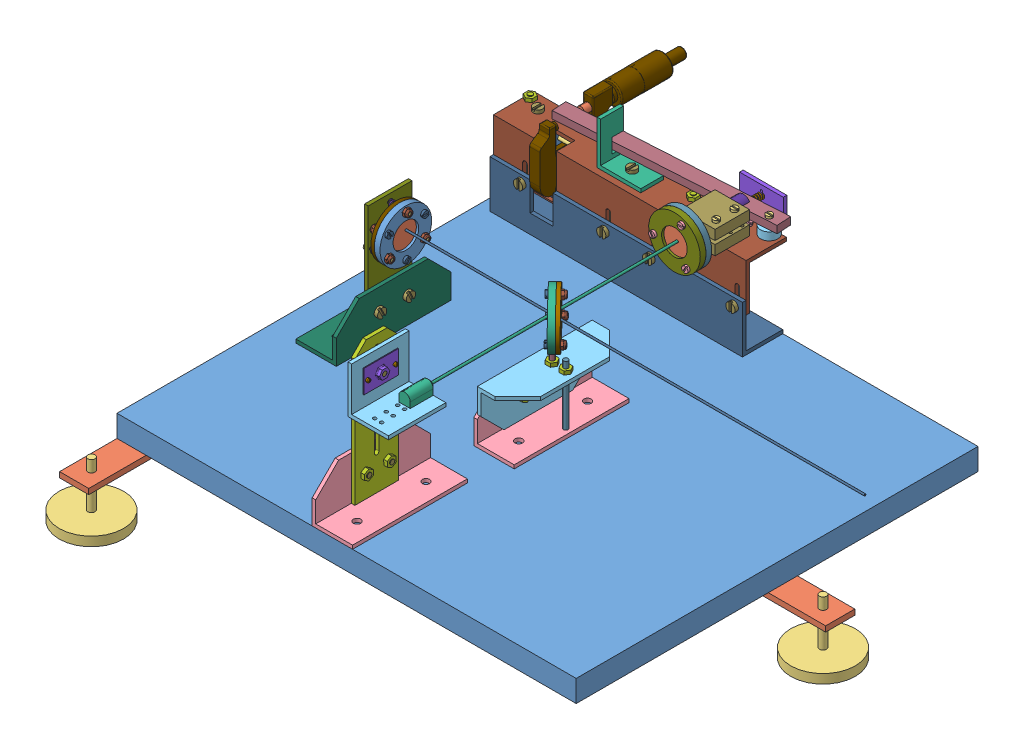
SolidWorks assembly Interferometro, configuration Default. Lengths in mm.
Overall size (495.22 180.12 500.25).
123 component instances, 46 part files, 21 mates.
Components (placement in the parent):
- Baser de Granito-1: Baser de Granito [Default] at (88.5564 -119.9075 34.7333) size (400 19 350)
- Pé de 3 pontos-2: Pé de 3 pontos [Default] at (-311.4436 -124.67 -145.2667) x (0 0 1) z (0 1 0) size (460 450 4.76)
- Pe_manipulo-1: Pe_manipulo [Default] at (-298.7436 -131.4123 69.7333) size (56.25 48 56.25)
- Pe_manipulo-2: Pe_manipulo [Default] at (123.5564 -131.4123 -145.2667) size (56.25 48 56.25)
- Pe_manipulo-3: Pe_manipulo [Default] at (-298.7436 -131.4123 -360.2667) x (0.821021 0 -0.570898) z (0.570898 0 0.821021) size (56.25 48 56.25)
- Suporte do divisor de feixe-1: Suporte do divisor de feixe [Default] at (-129.8734 -86.0499 -144.513) x (0 0 -1) z (1 0 0) size (100 102.86 41.95)
  - Base do divisor-1: Base do divisor [Default] at (-48.2463 -11.7326 33.4299) size (100 41.23 35.2)
  - Base do divisor B-1: Base do divisor B [Default] at (51.7537 28.2674 36.5549) x (-1 0 0) z (0 0 1) size (100 41.23 35.2)
  - Fixador dodivisor de feixe_frontal-1: Fixador dodivisor de feixe_frontal [Default] at (0.0337 65.5054 14.7406) x (0.688011 0 0.7257) z (-0.7257 0 0.688011) size (5 42.5 45)
  - Porca M4-1: Porca M4 [Default] at (1.7537 31.3924 16.5549) size (7.78 3.12 8.95)
  - Porca M4-2: Porca M4 [Default] at (1.7537 25.1424 16.5549) size (7.78 3.12 8.95)
  - Divisor de feixe-1: Divisor de feixe [Default] at (1.4097 65.5054 16.192) x (0.7257 0 -0.688011) z (0.688011 0 0.7257) size (25.4 25.4 3)
  - Arruela do Fixador do divisor de feixe-1: Arruela do Fixador do divisor de feixe [Default] at (3.4737 65.5054 18.3691) x (0.688011 0 0.7257) z (-0.7257 0 0.688011) size (3 42.5 45)
  - Parafuso Padrao M3 10-1: Parafuso Padrao M3 10 [Default] at (-1.3424 83.5054 13.2892) x (0.7257 0 -0.688011) z (0.688011 0 0.7257) size (5.45 5.45 14)
  - Porca M3-1: Porca M3 [Default] at (5.5378 83.5054 20.5462) x (0.725692 0.004853 -0.688003) z (0.003522 -0.999988 -0.003339) size (6.52 3.8 6.82)
  - Parafuso Padrao M3 10-2: Parafuso Padrao M3 10 [Default] at (9.9702 56.5054 2.5642) x (-0.36285 -0.866025 0.344005) z (0.688011 0 0.7257) size (5.45 5.45 14)
  - Parafuso Padrao M3 10-3: Parafuso Padrao M3 10 [Default] at (-12.6549 56.5054 24.0142) x (-0.36285 0.866025 0.344005) z (0.688011 0 0.7257) size (5.45 5.45 14)
  - Porca M3-2: Porca M3 [Default] at (16.8503 56.5054 9.8212) x (-0.359796 -0.868442 0.34111) z (-0.630228 0.495791 0.597497) size (6.52 3.8 6.82)
  - Porca M3-3: Porca M3 [Default] at (-5.7748 56.5054 31.2712) x (-0.365896 0.863589 0.346893) z (0.626707 0.504197 -0.594158) size (6.52 3.8 6.82)
  - Parafuso Padrao M4 16-1: Parafuso Padrao M4 16 [Default] at (14.8037 8.2674 -1.7681) x (1 0 0) z (0 1 0) size (8 13 8)
  - Porca M4-3: Porca M4 [Default] at (14.8037 8.2674 7.6069) x (1 0 0) z (0 1 0) size (7.78 3.12 8.95)
  - Porca M4-5: Porca M4 [Default] at (-11.2963 8.2674 7.6069) x (-0.995163 -0.09824 0) z (0.09824 -0.995163 0) size (7.78 3.12 8.95)
  - Parafuso Padrao M4 16-3: Parafuso Padrao M4 16 [Default] at (-11.2963 8.2674 -1.7681) x (1 0 0) z (0 1 0) size (8 13 8)
  - Haste M4-2: Haste M4 [Default] at (1.7537 20.5054 16.5549) x (0.189668 0 -0.981848) z (0.981848 0 0.189668) size (4 30 4)
  - Haste M4 Longa-2: Haste M4 Longa [Default] at (1.7537 -14.8576 28.4299) size (4 55 4)
  - Porca M4-7: Porca M4 [Default] at (1.7537 25.1424 28.4299) size (7.78 3.12 8.95)
  - Porca M4-8: Porca M4 [Default] at (1.7537 31.3924 28.4299) size (7.78 3.12 8.95)
- Espelho fixo-1: Espelho fixo [Default] at (-245.7834 -84.2987 -136.4219) x (0 0 1) z (-1 0 0) size (100 109.78 49.57)
  - Base do esplho fixo-1: Base do esplho fixo [Default] at (-59.6936 -13.4838 40.6602) size (100 41.23 35.2)
  - Coluna-1: Coluna [Default] at (9.3564 27.4324 8.5872) size (38.1 85 3.12)
  - Mola-1: Mola [Default] at (-9.6747 80.4368 2.5872) size (6.35 5.63 7.54)
  - Mola-2: Mola [Default] at (5.9282 53.474 2.5872) size (6.35 5.63 7.54)
  - Mola-3: Mola [Default] at (-25.1875 53.4779 2.5872) size (6.35 5.63 7.54)
  - Arruela do Fixador-1: Arruela do Fixador [Default] at (-9.6936 62.4324 -0.1128) x (0 0 1) z (-0.5 -0.866025 0) size (3 45 45)
  - Fixador do espelho_frontal-1: Fixador do espelho_frontal [Default] at (-9.6936 62.4324 -5.1128) x (0 0 1) z (-1 0 0) size (5 45 45)
  - Espelho-1: Espelho [Default] at (-9.6936 62.4324 -3.1128) size (25.4 25.4 3)
  - Parafuso Padrao M4 16-1: Parafuso Padrao M4 16 [Default] at (3.3564 6.5162 5.4622) x (0.907366 -0.420341 0) z (0.420341 0.907366 0) size (8 13 8)
  - Porca M4-1: Porca M4 [Default] at (3.3564 6.5162 14.8372) x (1 0 0) z (0 1 0) size (7.78 3.12 8.95)
  - Parafuso Padrao M4 16-2: Parafuso Padrao M4 16 [Default] at (-21.7436 6.5162 5.4622) x (0.907366 -0.420341 0) z (0.420341 0.907366 0) size (8 13 8)
  - Porca M4-2: Porca M4 [Default] at (-21.7436 6.5162 14.8372) x (1 0 0) z (0 1 0) size (7.78 3.12 8.95)
  - Parafuso Padrao M3 20-1: Parafuso Padrao M3 20 [Default] at (-9.6936 80.4324 13.7122) x (-0.923728 -0.383049 0) z (0 0 -1) size (5.45 5.45 22)
  - Porca M3-1: Porca M3 [Default] at (-9.6936 80.4324 -5.1128) x (1 0 0) z (0 1 0) size (6.52 3.8 6.82)
  - Parafuso Padrao M3 20-2: Parafuso Padrao M3 20 [Default] at (-25.282 53.4324 13.7122) x (0.793594 -0.608447 0) z (0 0 -1) size (5.45 5.45 22)
  - Parafuso Padrao M3 20-3: Parafuso Padrao M3 20 [Default] at (5.8949 53.4324 13.7122) x (0.130134 0.991496 0) z (0 0 -1) size (5.45 5.45 22)
  - Porca M3-2: Porca M3 [Default] at (-25.282 53.4324 -5.1128) x (-0.5 0.866025 0) z (-0.866025 -0.5 0) size (6.52 3.8 6.82)
  - Porca M3-3: Porca M3 [Default] at (5.8949 53.4324 -5.1128) x (-0.5 -0.866025 0) z (0.866025 -0.5 0) size (6.52 3.8 6.82)
  - Parafuso Padrao M3 10-1: Parafuso Padrao M3 10 [Default] at (-25.282 71.4324 -7.1128) size (5.45 5.45 14)
  - Porca M3-4: Porca M3 [Default] at (-25.3144 72.932 2.8872) x (1 0 0) z (0 -1 0) size (6.52 3.8 6.82)
  - Porca M3-5: Porca M3 [Default] at (-10.9761 43.6545 2.8872) x (-0.5 0.866025 0) z (0.866025 0.5 0) size (6.52 3.8 6.82)
  - Porca M3-6: Porca M3 [Default] at (7.2099 70.7106 2.8872) x (-0.5 -0.866025 0) z (-0.866025 0.5 0) size (6.52 3.8 6.82)
  - Parafuso Padrao M3 10-2: Parafuso Padrao M3 10 [Default] at (-9.6936 44.4324 -7.1128) x (-0.5 0.866025 0) z (0 0 1) size (5.45 5.45 14)
  - Parafuso Padrao M3 10-3: Parafuso Padrao M3 10 [Default] at (5.8949 71.4324 -7.1128) x (-0.5 -0.866025 0) z (0 0 1) size (5.45 5.45 14)
- Suporte do LASER-1: Suporte do LASER [Default] at (-143.3517 -88.5516 -23.7006) x (0 0 -1) z (1 0 0) size (299 123.12 44.45)
  - Base do LASER-1: Base do LASER [Default] at (-58.434 -9.2309 37.1061) size (100 41.23 35.2)
  - Base do LASER 2-1: Base do LASER 2 [Default] at (-33.434 63.8941 43.3561) size (50 41.23 35.2)
  - Parafuso Padrao M4 16-1: Parafuso Padrao M4 16 [Default] at (1.566 10.7691 1.9081) x (-0.976419 -0.215883 0) z (0.215883 -0.976419 0) size (8 13 8)
  - Porca M4-1: Porca M4 [Default] at (1.566 10.7691 8.1581) x (1 0 0) z (0 -1 0) size (7.78 3.12 8.95)
  - Parafuso Padrao M4 16-2: Parafuso Padrao M4 16 [Default] at (-8.434 84.0234 5.0331) x (1 0 0) z (0 1 0) size (8 13 8)
  - LASER-1: LASER [Default] at (16.566 68.8941 27.3561) x (0 0 1) z (-1 0 0) size (10 10 244)
  - Coluna do LASER-2: Coluna do LASER [Default] at (10.616 -9.2309 5.0331) size (38.1 120 3.12)
  - Porca M4-3: Porca M4 [Default] at (-18.434 10.7691 8.1581) x (1 0 0) z (0 -1 0) size (7.78 3.12 8.95)
  - Parafuso Padrao M4 16-3: Parafuso Padrao M4 16 [Default] at (-18.434 10.7691 1.9081) x (-0.976419 -0.215883 0) z (0.215883 -0.976419 0) size (8 13 8)
  - Porca M4 com grampo-1: Porca M4 com grampo [Default] at (-8.434 84.0234 12.0331) x (0 -1 0) z (-1 0 0) size (20 3.88 30)
  - Parafuso 22-1: Parafuso 22 [Default] at (-20.434 84.0234 12.0331) x (1 0 0) z (0 -1 0) size (3.2 5.55 3.24)
  - Parafuso 22-2: Parafuso 22 [Default] at (3.566 84.0234 12.0331) x (1 0 0) z (0 -1 0) size (3.2 5.55 3.24)
- Espelho regulavel-1: Espelho regulavel [Default] at (-164.1321 -91.633 -267.4552) x (-1 0 0) z (0 0 -1) size (220.22 110.65 148.54)
  - Base fixa do espelho Regulavel-1: Base fixa do espelho Regulavel [Default] at (-82.6886 -6.1494 47.8115) size (220 41.23 35.2)
  - Base do espelho Regulavel-1: Base do espelho Regulavel [Default] at (117.3114 58.8506 50.9365) x (-1 0 0) z (0 0 1) size (220 41.23 35.2)
  - Trilo de Nylon-1: Trilo de Nylon [Default] at (-65.6886 61.9756 35.7385) x (-1 0 0) z (0 0 -1) size (30 20 30)
  - Alvanca de reducao-1: Alvanca de reducao [Default] at (102.5165 75.1506 43.9693) x (0.998146 0 -0.060863) z (-0.060863 0 -0.998146) size (185 6.35 14.7)
  - Arruela do Fixador fechada-1: Arruela do Fixador fechada [Default] at (-47.6886 71.9756 -1.5991) x (0 0 -1) z (0.923728 0.383049 0) size (5 45 45)
  - Parafuso Padrao M5-1: Parafuso Padrao M5 [Default] at (-47.6886 71.9756 -6.5991) x (0.994046 0.108962 0) z (0.108962 -0.994046 0) size (10 12 9.8)
  - Espelho-1: Espelho [Default] at (-47.6886 71.9756 -9.5991) size (25.4 25.4 3)
  - Fixador do espelho_frontal_movel-1: Fixador do espelho_frontal_movel [Default] at (-47.6886 71.9756 -11.5991) x (0 0 1) z (-0.923728 -0.383049 0) size (5 45 45)
  - Guia linear-3: Guia linear [Default] at (-47.6886 71.9756 48.4009) x (-1 0 0) z (0 0 -1) size (12.7 12.7 60)
  - Micrometro-1: Micrometro [Default] at (96.6114 48.8506 52.9365) x (0 0 1) z (-1 0 0) size (128.44 56.67 19.2)
  - Base do micrometro A-1: Base do micrometro A [Default] at (47.1134 55.7256 50.9365) x (0 0 -1) z (-1 0 0) size (25 41.23 35.2)
  - Base do micrometro A-2: Base do micrometro A [Default] at (137.3114 55.7256 25.9365) x (0 0 1) z (1 0 0) size (25 41.23 35.2)
  - Eixo do micrometro-1: Eixo do micrometro [Default] at (92.1114 71.9235 96.5779) x (0.963366 0.268189 0) z (-0.268189 0.963366 0) size (7 50 7)
  - Parafuso Padrao M4-1: Parafuso Padrao M4 [Default] at (79.1864 22.6256 38.4365) x (0 1 0) z (0 0 1) size (8 33 8)
  - Porca M4-1: Porca M4 [Default] at (108.3634 22.6256 38.4365) x (0 1 0) z (0 0 1) size (7.78 3.12 8.95)
  - Parafuso Padrao M4-2: Parafuso Padrao M4 [Default] at (79.1864 51.1928 38.4365) x (0 1 0) z (0 0 1) size (8 33 8)
  - Porca M4-2: Porca M4 [Default] at (108.3634 51.1928 38.4365) x (0 1 0) z (0 0 1) size (7.78 3.12 8.95)
  - Parafuso Padrao M4 16-1: Parafuso Padrao M4 16 [Default] at (121.2749 61.9756 38.4365) size (8 13 8)
  - Parafuso Padrao M4 16-2: Parafuso Padrao M4 16 [Default] at (63.1499 61.9756 38.4365) size (8 13 8)
  - Porca M4-3: Porca M4 [Default] at (121.2749 52.6006 38.4365) size (7.78 3.12 8.95)
  - Porca M4-4: Porca M4 [Default] at (63.1499 52.6006 38.4365) size (7.78 3.12 8.95)
  - Parafuso Padrao M3-1: Parafuso Padrao M3 [Default] at (-63.1886 56.8506 21.7385) x (-0.377487 0 -0.926015) z (0 1 0) size (5.45 5.45 12)
  - Parafuso Padrao M3-2: Parafuso Padrao M3 [Default] at (-63.1886 56.8506 31.7385) x (-0.377487 0 -0.926015) z (0 1 0) size (5.45 5.45 12)
  - Parafuso Padrao M3-3: Parafuso Padrao M3 [Default] at (-38.1886 56.8506 21.7385) x (-0.377487 0 -0.926015) z (0 1 0) size (5.45 5.45 12)
  - Parafuso Padrao M3-4: Parafuso Padrao M3 [Default] at (-38.1886 56.8506 31.7385) x (-0.377487 0 -0.926015) z (0 1 0) size (5.45 5.45 12)
  - Parafuso Padrao M3 20-1: Parafuso Padrao M3 20 [Default] at (-59.6886 83.9756 12.7385) x (1 0 0) z (0 -1 0) size (5.45 5.45 22)
  - Parafuso Padrao M3 20-2: Parafuso Padrao M3 20 [Default] at (-59.6886 83.9756 28.7385) x (1 0 0) z (0 -1 0) size (5.45 5.45 22)
  - Parafuso Padrao M4 16-3: Parafuso Padrao M4 16 [Default] at (-75.1886 25.7256 12.6135) x (1 0 0) z (0 1 0) size (8 13 8)
  - Parafuso Padrao M4 16-4: Parafuso Padrao M4 16 [Default] at (-2.6886 25.7256 12.6135) x (1 0 0) z (0 1 0) size (8 13 8)
  - Parafuso Padrao M4 16-5: Parafuso Padrao M4 16 [Default] at (37.3114 25.7256 12.6135) x (1 0 0) z (0 1 0) size (8 13 8)
  - Parafuso Padrao M4 16-6: Parafuso Padrao M4 16 [Default] at (109.8114 25.7256 12.6135) x (1 0 0) z (0 1 0) size (8 13 8)
  - Porca M4-5: Porca M4 [Default] at (37.3114 25.7256 21.9885) x (1 0 0) z (0 1 0) size (7.78 3.12 8.95)
  - Porca M4-6: Porca M4 [Default] at (109.8114 25.7256 21.9885) x (1 0 0) z (0 1 0) size (7.78 3.12 8.95)
  - Porca M4-7: Porca M4 [Default] at (-75.1886 25.7256 21.9885) x (1 0 0) z (0 1 0) size (7.78 3.12 8.95)
  - Porca M4-8: Porca M4 [Default] at (-2.6886 25.7256 21.9885) x (1 0 0) z (0 1 0) size (7.78 3.12 8.95)
  - Bucha-1: Bucha [Default] at (-72.6886 68.7756 45.9365) x (1 0 0) z (0 -1 0) size (15 15 6.8)
  - Parafuso Padrao M3 20-3: Parafuso Padrao M3 20 [Default] at (-72.6886 77.1506 45.9365) x (1 0 0) z (0 -1 0) size (5.45 5.45 22)
  - Porca M3-1: Porca M3 [Default] at (-72.6886 58.8506 45.9365) x (-0.837169 0 -0.546944) z (-0.546944 0 0.837169) size (6.52 3.8 6.82)
  - Suporte da alavanca-1: Suporte da alavanca [Default] at (14.2114 61.9756 40.9479) x (-1 0 0) z (0 0 -1) size (38.1 38.1 20)
  - Parafuso Padrao M4 16-7: Parafuso Padrao M4 16 [Default] at (31.6989 65.1006 30.9479) size (8 13 8)
  - Porca M4-9: Porca M4 [Default] at (31.6989 55.7256 30.9479) size (7.78 3.12 8.95)
  - Parafuso Padrao M3-5: Parafuso Padrao M3 [Default] at (-54.5835 88.6027 -13.5991) size (5.45 5.45 12)
  - Parafuso Padrao M3-6: Parafuso Padrao M3 [Default] at (-58.6406 57.6909 -13.5991) x (-0.5 0.866025 0) z (0 0 1) size (5.45 5.45 12)
  - Parafuso Padrao M3-7: Parafuso Padrao M3 [Default] at (-29.8416 69.6331 -13.5991) x (-0.5 -0.866025 0) z (0 0 1) size (5.45 5.45 12)
  - Haste M4 Longa 2-1: Haste M4 Longa 2 [Default] at (133.3114 -9.2744 43.8115) size (4 75 4)
  - Porca M4-10: Porca M4 [Default] at (133.3114 61.9756 43.8115) size (7.78 3.12 8.95)
  - Porca M4-11: Porca M4 [Default] at (133.3114 52.6006 43.8115) size (7.78 3.12 8.95)
  - Haste M4 Longa 2-2: Haste M4 Longa 2 [Default] at (-12.6886 -9.2744 39.8115) size (4 75 4)
  - Porca M4-13: Porca M4 [Default] at (-12.6886 61.9756 39.8115) size (7.78 3.12 8.95)
  - Porca M4-14: Porca M4 [Default] at (-12.6886 55.7256 39.8115) size (7.78 3.12 8.95)
  - Esticador da mola-1: Esticador da mola [Default] at (-64.9597 55.7256 39.0615) x (0 0 -1) z (1 0 0) size (30 20 38.1)
  - Mola do guia linear-1: Mola do guia linear [Default] at (-45.9871 67.7595 66.2365) x (-0.923728 -0.383049 0) z (0 0 -1) size (6.35 5.57 11.5)
  - Parafuso Padrao M3-8: Parafuso Padrao M3 [Default] at (-35.3778 63.9756 44.0615) x (1 0 0) z (0 -1 0) size (5.45 5.45 12)
  - Parafuso Padrao M3-9: Parafuso Padrao M3 [Default] at (-56.4416 63.9756 44.0615) x (1 0 0) z (0 -1 0) size (5.45 5.45 12)
  - Porca M3-2: Porca M3 [Default] at (-35.3778 55.7256 44.0615) x (-0.837169 0 -0.546944) z (-0.546944 0 0.837169) size (6.52 3.8 6.82)
  - Porca M3-3: Porca M3 [Default] at (-56.4416 55.7256 44.0615) x (-0.837169 0 -0.546944) z (-0.546944 0 0.837169) size (6.52 3.8 6.82)
- Feixe de LASER-1: Feixe de LASER [Default] at (157.3294 -19.5553 -148.1071) x (0 0 1) z (-1 0 0) size (1.6 1.6 400)
Mates (geometry in assembly coordinates):
- Coincident1: coincident: plane of Baser de Granito-1 through (88.5564 -119.9075 -315.2667) normal (0 -1 0); plane of Pé de 3 pontos-2 through (138.5564 -119.9075 84.7333) normal (0 1 0)
- Coincident2: coincident: plane of Baser de Granito-1 through (-311.4436 -100.9075 34.7333) normal (-1 0 0); plane of Pé de 3 pontos-2 through (-311.4436 -119.9075 -375.2667) normal (-1 0 0)
- Distance1: distance = 50 mm: plane of Baser de Granito-1 through (88.5564 -100.9075 34.7333) normal (0 0 1); plane of Pé de 3 pontos-2 through (-311.4436 -119.9075 84.7333) normal (0 0 1)
- Concentric1: concentric: cylinder of Pé de 3 pontos-2 through (-298.7436 -124.67 69.7333) axis (0 1 0) radius 3.125; cylinder of Pe_manipulo-1 through (-298.7436 -131.4123 69.7333) axis (0 -1 0) radius 3.125
- Distance2: distance = 10 mm: plane of Pé de 3 pontos-2 through (138.5564 -119.9075 84.7333) normal (0 1 0); plane of Pe_manipulo-1 through (-298.7436 -109.9075 69.7333) normal (0 1 0)
- Concentric2: concentric: cylinder of Pé de 3 pontos-2 through (123.5564 -124.67 -145.2667) axis (0 1 0) radius 3.125; cylinder of Pe_manipulo-2 through (123.5564 -131.4123 -145.2667) axis (0 -1 0) radius 3.125
- Distance3: distance = 10 mm: plane of Pé de 3 pontos-2 through (138.5564 -119.9075 84.7333) normal (0 1 0); plane of Pe_manipulo-2 through (123.5564 -109.9075 -145.2667) normal (0 1 0)
- Concentric3: concentric: cylinder of Pé de 3 pontos-2 through (-298.7436 -124.67 -360.2667) axis (0 1 0) radius 3.125; cylinder of Pe_manipulo-3 through (-298.7436 -131.4123 -360.2667) axis (0 -1 0) radius 3.125
- Distance4: distance = 10 mm: plane of Pé de 3 pontos-2 through (138.5564 -119.9075 84.7333) normal (0 1 0); plane of Pe_manipulo-3
- Coincident7: coincident: plane of Baser de Granito-1 through (88.5564 -100.9075 -315.2667) normal (0 1 0); plane of Suporte do divisor de feixe-1/Base do divisor-1 through (-96.4436 -100.9075 -196.2667) normal (0 -1 0)
- Coincident8: coincident: plane of Baser de Granito-1 through (88.5564 -100.9075 -315.2667) normal (0 1 0); plane of Espelho fixo-1/Base do esplho fixo-1 through (-286.4436 -100.9075 -96.1154) normal (0 -1 0)
- Distance5: distance = 25 mm: plane of Baser de Granito-1 through (-311.4436 -100.9075 34.7333) normal (-1 0 0); plane of Espelho fixo-1/Base do esplho fixo-1 through (-286.4436 -100.9075 -96.1154) normal (-1 0 0)
- Coincident10: coincident: plane of Baser de Granito-1 through (88.5564 -100.9075 34.7333) normal (0 0 1); plane of Suporte do LASER-1/Base do LASER-1 through (-141.4436 -97.7825 34.7333) normal (0 0 1)
- Coincident11: coincident: plane of Baser de Granito-1 through (88.5564 -100.9075 -315.2667) normal (0 1 0); plane of Suporte do LASER-1/Base do LASER-1 through (-106.2456 -100.9075 -65.2667) normal (0 -1 0)
- Distance6: distance = 170 mm: plane of Baser de Granito-1 through (-311.4436 -100.9075 34.7333) normal (-1 0 0); plane of Suporte do LASER-1/Base do LASER-1 through (-141.4436 -97.7825 -65.2667) normal (-1 0 0)
- Distance7: distance = 231 mm: plane of Baser de Granito-1 through (88.5564 -100.9075 34.7333) normal (0 0 1); plane of Suporte do divisor de feixe-1/Base do divisor-1 through (-131.6416 -97.7825 -196.2667) normal (0 0 -1)
- Distance8: distance = 185 mm: plane of Baser de Granito-1 through (88.5564 -100.9075 34.7333) normal (1 0 0); line of Suporte do divisor de feixe-1/Base do divisor-1 through (-96.4436 -97.7825 -196.2667) axis (0 0 1)
- Coincident12: coincident: plane of Baser de Granito-1 through (88.5564 -100.9075 -315.2667) normal (0 1 0); plane of Espelho regulavel-1/Base fixa do espelho Regulavel-1 through (-301.4436 -100.9075 -315.2667) normal (0 -1 0)
- Coincident13: coincident: plane of Baser de Granito-1 through (88.5564 -100.9075 -315.2667) normal (0 0 -1); plane of Espelho regulavel-1/Base fixa do espelho Regulavel-1 through (-301.4436 -100.9075 -315.2667) normal (0 0 -1)
- Distance9: distance = 170 mm: plane of Baser de Granito-1 through (88.5564 -100.9075 34.7333) normal (1 0 0); plane of Espelho regulavel-1/Base fixa do espelho Regulavel-1 through (-81.4436 -97.7825 -280.0687) normal (1 0 0)
- Coincident14: coincident: plane of Espelho fixo-1/Espelho-1 through (-242.6706 -21.8663 -146.1154) normal (1 0 0); plane of Feixe de LASER-1 through (-242.6706 -19.5553 -148.1071) normal (-1 0 0)
